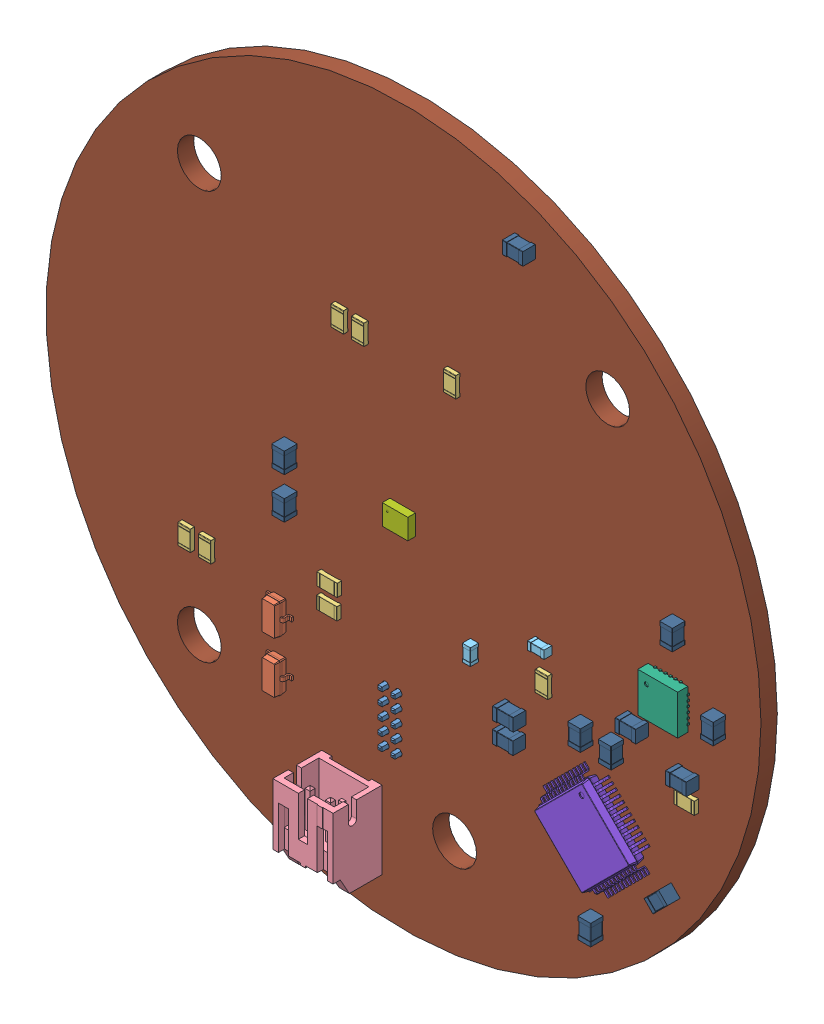
SolidWorks assembly BansheePCB, configuration Default. Lengths in mm.
Overall size (70.03 70.03 10.55).
68 component instances, 11 part files, 0 mates.
Components (placement in the parent):
- PT0.step-1: PT0.step [Default] at origin size (70.03 70.03 10.55)
  - PinHeader_2x05_P1.27mm_Vertical.step-1: PinHeader_2x05_P1.27mm_Vertical.step [Default] at (148.25 -130.23 -0.05) x (1 0 0) z (0 0 -1) size (3.4 6.35 6.3)
    - SOLID.step-1: SOLID.step [Default] at origin size (3.4 6.35 6.3)
  - SOT-23.step-1: SOT-23.step [Default] at (138 -129 1.65) size (2.5 3 1.2)
    - SOLID-0.step-1: SOLID-0.step [Default] at origin size (2.5 3 1.2)
  - SOT-23.step-2: SOT-23.step [Default] at (138 -124 1.65) size (2.5 3 1.2)
    - SOLID-0.step-1: SOLID-0.step [Default] at origin size (2.5 3 1.2)
  - R_0805_2012Metric.step-1: R_0805_2012Metric.step [Default] at (177.975 -120 1.65) size (2 1.2 0.45)
    - SOLID-1.step-1: SOLID-1.step [Default] at origin size (2 1.2 0.45)
  - R_0805_2012Metric.step-2: R_0805_2012Metric.step [Default] at (144 -95.975 1.65) x (0 1 0) z (0 0 1) size (2 1.2 0.45)
    - SOLID-1.step-1: SOLID-1.step [Default] at origin size (2 1.2 0.45)
  - R_0805_2012Metric.step-3: R_0805_2012Metric.step [Default] at (146 -96.025 1.65) x (0 1 0) z (0 0 1) size (2 1.2 0.45)
    - SOLID-1.step-1: SOLID-1.step [Default] at origin size (2 1.2 0.45)
  - JST_PH_S2B-PH-K_1x02_P2.00mm_Horizontal.step-1: JST_PH_S2B-PH-K_1x02_P2.00mm_Horizontal.step [Default] at (146 -140 1.65) x (-1 0 0) z (0 0 1) size (5.9 7.6 8.25)
    - SOLID-2.step-1: SOLID-2.step [Default] at origin size (5.9 7.6 8.25)
  - C_0603_1608Metric.step-1: C_0603_1608Metric.step [Default] at (163.7875 -114 1.65) size (1.6 0.8 0.8)
    - SOLID-3.step-1: SOLID-3.step [Default] at origin size (1.6 0.8 0.8)
  - C_0603_1608Metric.step-2: C_0603_1608Metric.step [Default] at (157 -117.7875 1.65) x (0 -1 0) z (0 0 1) size (1.6 0.8 0.8)
    - SOLID-3.step-1: SOLID-3.step [Default] at origin size (1.6 0.8 0.8)
  - QFN-24-1EP_4x4mm_P0.5mm_EP2.7x2.6mm.step-1: QFN-24-1EP_4x4mm_P0.5mm_EP2.7x2.6mm.step [Default] at (176.05 -112.25 1.65) size (4 4 1.1)
    - SOLID-4.step-1: SOLID-4.step [Default] at origin size (4 4 1.1)
  - Bosch_LGA-8_2x2.5mm_P0.65mm_ClockwisePinNumbering.step-1: Bosch_LGA-8_2x2.5mm_P0.65mm_ClockwisePinNumbering.step [Default] at (150 -110 1.65) size (2.5 2 0.78)
    - SOLID-5.step-1: SOLID-5.step [Default] at origin size (2.5 2 0.78)
  - LQFP-48_7x7mm_P0.5mm.step-1: LQFP-48_7x7mm_P0.5mm.step [Default] at (169 -127 1.65) x (0.707107 -0.707107 0) z (0 0 1) size (9 9 1.5)
    - SOLID-6.step-1: SOLID-6.step [Default] at origin size (9 9 1.5)
  - R_0805_2012Metric.step-4: R_0805_2012Metric.step [Default] at (155 -95.975 1.65) x (0 1 0) z (0 0 1) size (2 1.2 0.45)
    - SOLID-1.step-1: SOLID-1.step [Default] at origin size (2 1.2 0.45)
  - R_0805_2012Metric.step-5: R_0805_2012Metric.step [Default] at (142.975 -121 1.65) size (2 1.2 0.45)
    - SOLID-1.step-1: SOLID-1.step [Default] at origin size (2 1.2 0.45)
  - R_0805_2012Metric.step-6: R_0805_2012Metric.step [Default] at (129 -122 1.65) x (0 1 0) z (0 0 1) size (2 1.2 0.45)
    - SOLID-1.step-1: SOLID-1.step [Default] at origin size (2 1.2 0.45)
  - R_0805_2012Metric.step-7: R_0805_2012Metric.step [Default] at (164 -116.975 1.65) x (0 -1 0) z (0 0 1) size (2 1.2 0.45)
    - SOLID-1.step-1: SOLID-1.step [Default] at origin size (2 1.2 0.45)
  - R_0805_2012Metric.step-8: R_0805_2012Metric.step [Default] at (143 -119 1.65) size (2 1.2 0.45)
    - SOLID-1.step-1: SOLID-1.step [Default] at origin size (2 1.2 0.45)
  - R_0805_2012Metric.step-9: R_0805_2012Metric.step [Default] at (131 -121.975 1.65) x (0 1 0) z (0 0 1) size (2 1.2 0.45)
    - SOLID-1.step-1: SOLID-1.step [Default] at origin size (2 1.2 0.45)
  - LED_0805_2012Metric.step-1: LED_0805_2012Metric.step [Default] at (149.025 -121 -0.05) x (-1 0 0) z (0 0 -1) size (2 1.25 1.1)
    - SOLID-7.step-1: SOLID-7.step [Default] at origin size (2 1.25 1.1)
  - LED_0805_2012Metric.step-2: LED_0805_2012Metric.step [Default] at (149.025 -119 -0.05) x (-1 0 0) z (0 0 -1) size (2 1.25 1.1)
    - SOLID-7.step-1: SOLID-7.step [Default] at origin size (2 1.25 1.1)
  - C_0805_2012Metric.step-1: C_0805_2012Metric.step [Default] at (177.975 -118 1.65) x (-1 0 0) z (0 0 1) size (2 1.25 1.25)
    - SOLID-8.step-1: SOLID-8.step [Default] at origin size (2 1.25 1.25)
  - C_0805_2012Metric.step-2: C_0805_2012Metric.step [Default] at (177 -106 1.65) x (0 -1 0) z (0 0 1) size (2 1.25 1.25)
    - SOLID-8.step-1: SOLID-8.step [Default] at origin size (2 1.25 1.25)
  - C_0805_2012Metric.step-3: C_0805_2012Metric.step [Default] at (181 -111.975 1.65) x (0 -1 0) z (0 0 1) size (2 1.25 1.25)
    - SOLID-8.step-1: SOLID-8.step [Default] at origin size (2 1.25 1.25)
  - C_0805_2012Metric.step-4: C_0805_2012Metric.step [Default] at (173.025 -116 1.65) x (-1 0 0) z (0 0 1) size (2 1.25 1.25)
    - SOLID-8.step-1: SOLID-8.step [Default] at origin size (2 1.25 1.25)
  - C_0805_2012Metric.step-5: C_0805_2012Metric.step [Default] at (139 -109.975 1.65) x (0 -1 0) z (0 0 1) size (2 1.25 1.25)
    - SOLID-8.step-1: SOLID-8.step [Default] at origin size (2 1.25 1.25)
  - C_0805_2012Metric.step-6: C_0805_2012Metric.step [Default] at (161.975 -81 1.65) size (2 1.25 1.25)
    - SOLID-8.step-1: SOLID-8.step [Default] at origin size (2 1.25 1.25)
  - C_0805_2012Metric.step-7: C_0805_2012Metric.step [Default] at (139 -114 1.65) x (0 -1 0) z (0 0 1) size (2 1.25 1.25)
    - SOLID-8.step-1: SOLID-8.step [Default] at origin size (2 1.25 1.25)
  - C_0805_2012Metric.step-8: C_0805_2012Metric.step [Default] at (161.025 -121 1.65) x (-1 0 0) z (0 0 1) size (2 1.25 1.25)
    - SOLID-8.step-1: SOLID-8.step [Default] at origin size (2 1.25 1.25)
  - C_0805_2012Metric.step-9: C_0805_2012Metric.step [Default] at (161 -123 1.65) x (-1 0 0) z (0 0 1) size (2 1.25 1.25)
    - SOLID-8.step-1: SOLID-8.step [Default] at origin size (2 1.25 1.25)
  - C_0805_2012Metric.step-10: C_0805_2012Metric.step [Default] at (171 -119.025 1.65) x (0 1 0) z (0 0 1) size (2 1.25 1.25)
    - SOLID-8.step-1: SOLID-8.step [Default] at origin size (2 1.25 1.25)
  - C_0805_2012Metric.step-11: C_0805_2012Metric.step [Default] at (176 -129.025 1.65) x (-0.707107 -0.707107 0) z (0 0 1) size (2 1.25 1.25)
    - SOLID-8.step-1: SOLID-8.step [Default] at origin size (2 1.25 1.25)
  - C_0805_2012Metric.step-12: C_0805_2012Metric.step [Default] at (168 -119.025 1.65) x (0 1 0) z (0 0 1) size (2 1.25 1.25)
    - SOLID-8.step-1: SOLID-8.step [Default] at origin size (2 1.25 1.25)
  - C_0805_2012Metric.step-13: C_0805_2012Metric.step [Default] at (169 -135.025 1.65) x (0 -1 0) z (0 0 1) size (2 1.25 1.25)
    - SOLID-8.step-1: SOLID-8.step [Default] at origin size (2 1.25 1.25)
  - COMPOUND.step-1: COMPOUND.step [Default] at origin size (70.03 70.03 1.6)
